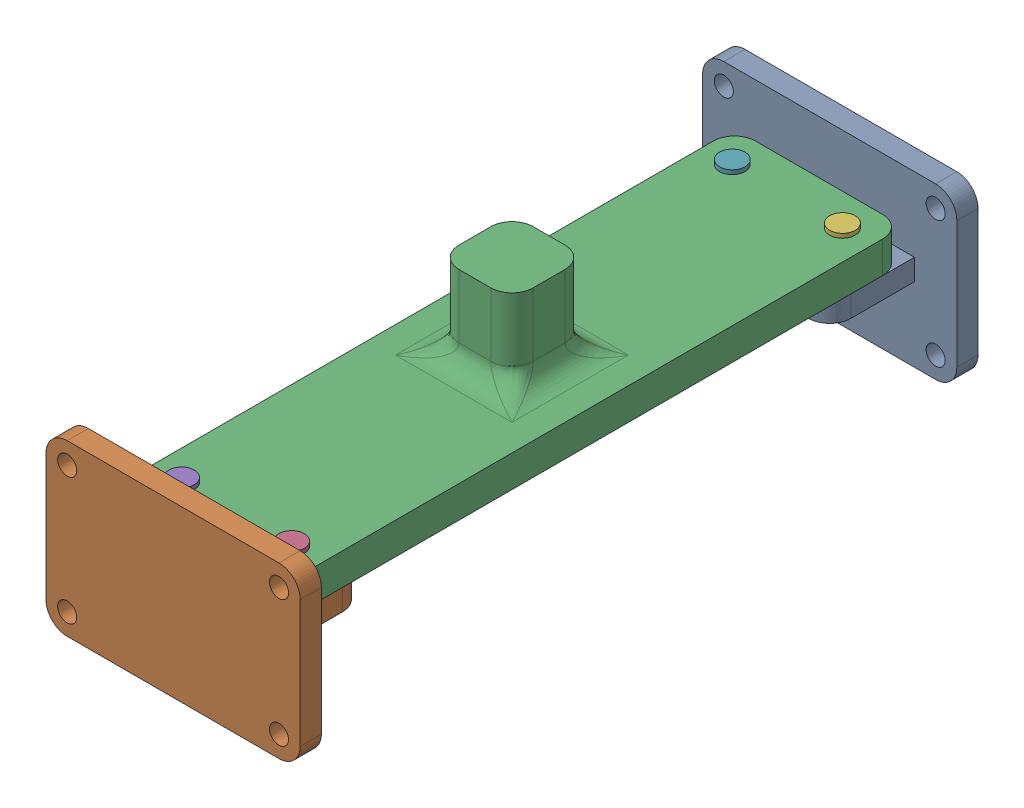
SolidWorks assembly Assem1, configuration Default. Lengths in mm.
Overall size (120 100 320).
6 component instances, 3 part files, 14 mates.
Components (placement in the parent):
- Part1-1: Part1 [Default] at (521.6719 851.2481 1503.4671) size (120 80 320)
- Part3-2: Part3 [Default] at (521.6719 871.2481 1353.4671) x (0 0 1) z (1 0 0) size (290 55 80)
- Part2-1: Part2 [Default] at (547.6719 871.2481 1483.4671) x (0.964504 0 0.26407) z (0 -1 0) size (12 12 29)
- Part2-2: Part2 [Default] at (495.6719 871.2481 1483.4671) x (1 0 0) z (0 -1 0) size (12 12 29)
- Part2-3: Part2 [Default] at (547.6719 846.2481 1223.4671) x (-0.161316 0 0.986903) z (0 1 0) size (12 12 29)
- Part2-4: Part2 [Default] at (495.6719 846.2481 1223.4671) x (1 0 0) z (0 1 0) size (12 12 29)
Mates (geometry in assembly coordinates):
- Concentric1: concentric aligned: cylinder of Part1-1 through (495.6719 891.2481 1483.4671) axis (0 -1 0) radius 4.5; cylinder of Part3-2 through (495.6719 871.2481 1483.4671) axis (0 -1 0) radius 4.5
- Concentric2: concentric aligned: cylinder of Part1-1 through (547.6719 891.2481 1483.4671) axis (0 -1 0) radius 4.5; cylinder of Part3-2 through (547.6719 871.2481 1483.4671) axis (0 -1 0) radius 4.5
- Concentric3: concentric anti-aligned: cylinder of Part1-1 through (495.6719 811.2481 1223.4671) axis (0 1 0) radius 4.5; cylinder of Part3-2 through (495.6719 871.2481 1223.4671) axis (0 -1 0) radius 4.5
- Concentric4: concentric anti-aligned: cylinder of Part1-1 through (547.6719 811.2481 1223.4671) axis (0 1 0) radius 4.5; cylinder of Part3-2 through (547.6719 871.2481 1223.4671) axis (0 -1 0) radius 4.5
- Concentric5: concentric anti-aligned: cylinder of Part3-2 through (547.6719 871.2481 1483.4671) axis (0 -1 0) radius 4.5; cylinder of Part2-1 through (547.6719 846.2481 1483.4671) axis (0 1 0) radius 4.5
- Coincident1: coincident anti-aligned: plane of Part3-2 through (521.6719 871.2481 1353.4671) normal (0 1 0); plane of Part2-1 through (547.6719 871.2481 1483.4671) normal (0 -1 0)
- Coincident2: coincident anti-aligned: plane of Part1-1 through (561.6719 846.2481 1463.4671) normal (0 -1 0); plane of Part2-1 through (547.6719 846.2481 1483.4671) normal (0 1 0)
- Concentric6: concentric anti-aligned: cylinder of Part3-2 through (495.6719 871.2481 1483.4671) axis (0 -1 0) radius 4.5; cylinder of Part2-2 through (495.6719 846.2481 1483.4671) axis (0 1 0) radius 4.5
- Coincident3: coincident anti-aligned: plane of Part3-2 through (521.6719 871.2481 1353.4671) normal (0 1 0); plane of Part2-2 through (495.6719 871.2481 1483.4671) normal (0 -1 0)
- Concentric7: concentric: cylinder of Part1-1 through (547.6719 811.2481 1223.4671) axis (0 1 0) radius 4.5; cylinder of Part2-3 through (547.6719 821.4202 1223.4671) axis (0 -1 0) radius 4.5
- Concentric8: concentric: cylinder of Part1-1 through (547.6719 811.2481 1223.4671) axis (0 1 0) radius 4.5; cylinder of Part2-3 through (547.6719 821.4202 1223.4671) axis (0 -1 0) radius 4.5
- Coincident4: coincident anti-aligned: plane of Part1-1 through (561.6719 846.2481 1243.4671) normal (0 -1 0); plane of Part2-3 through (547.6719 846.2481 1223.4671) normal (0 1 0)
- Concentric9: concentric: cylinder of Part1-1 through (495.6719 811.2481 1223.4671) axis (0 1 0) radius 4.5; cylinder of Part2-4 through (495.6719 871.2481 1223.4671) axis (0 -1 0) radius 4.5
- Coincident5: coincident anti-aligned: plane of Part1-1 through (561.6719 846.2481 1243.4671) normal (0 -1 0); plane of Part2-4 through (495.6719 846.2481 1223.4671) normal (0 1 0)
